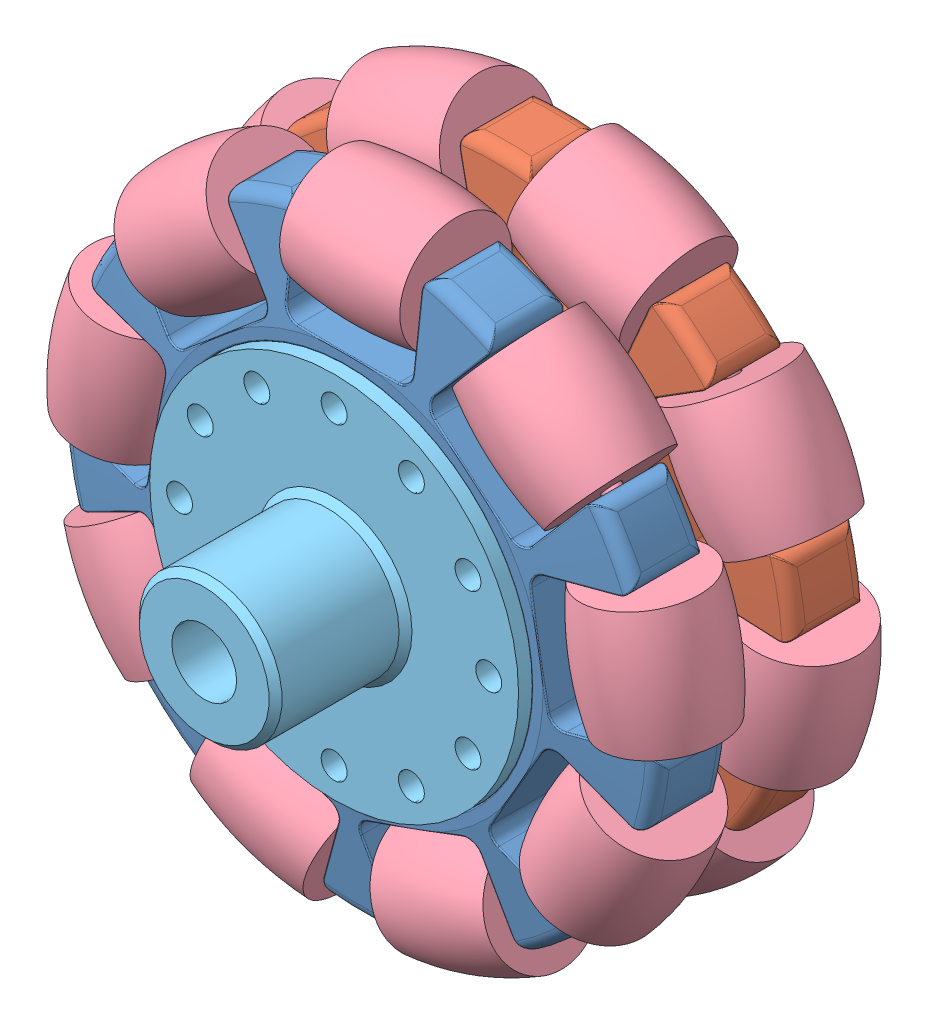
SolidWorks assembly banhxe, configuration Default. Lengths in mm.
Overall size (124.48 124.98 61.51).
22 component instances, 5 part files, 17 mates.
Components (placement in the parent):
- omniwheel_1-1: omniwheel_1 [Default] at (-17.0114 53.5739 73.2518) size (91.98 90.63 15.09)
- omniwheel_2-1: omniwheel_2 [Default] at (-17.0114 53.5739 37.2518) x (-0.5 -0.866025 0) z (0 0 -1) size (91.98 90.63 15.09)
- Part1^banhxe-1: Part1^banhxe [Default] at (-17.0114 53.5739 59.2518) x (-1 0 0) z (0 0 -1) size (56.8 56.8 18) (virtual)
- roller-1: roller [Default] at (-17.0114 132.519 53.0151) x (1 0 0) z (0 -0.314487 -0.949262) size (24.1 19 19)
- roller-3: roller [Default] at (33.7335 114.0494 53.0151) x (0.766044 -0.642788 0) z (-0.202148 -0.240911 -0.949262) size (24.1 19 19)
- roller-4: roller [Default] at (60.7343 67.2826 53.0151) x (0.173648 -0.984808 0) z (-0.309709 -0.05461 -0.949262) size (24.1 19 19)
- roller-5: roller [Default] at (51.357 14.1014 53.0151) x (-0.5 -0.866025 0) z (-0.272353 0.157243 -0.949262) size (24.1 19 19)
- roller-6: roller [Default] at (9.9894 -20.6102 53.0151) x (-0.939693 -0.34202 0) z (-0.107561 0.295521 -0.949262) size (24.1 19 19)
- roller-7: roller [Default] at (-44.0123 -20.6102 53.0151) x (-0.939693 0.34202 0) z (0.107561 0.295521 -0.949262) size (24.1 19 19)
- roller-8: roller [Default] at (-85.3799 14.1014 53.0151) x (-0.5 0.866025 0) z (0.272353 0.157243 -0.949262) size (24.1 19 19)
- roller-9: roller [Default] at (-94.7572 67.2826 53.0151) x (0.173648 0.984808 0) z (0.309709 -0.05461 -0.949262) size (24.1 19 19)
- roller-10: roller [Default] at (-67.7564 114.0494 53.0151) x (0.766044 0.642788 0) z (0.202148 -0.240911 -0.949262) size (24.1 19 19)
- roller-11: roller [Default] at (-17.5454 53.8822 51.7918) x (0.5 0.866025 0) z (-0.150538 0.086913 0.984776) size (24.1 19 19)
- roller-12: roller [Default] at (-17.6186 53.4669 51.7918) x (-0.173648 0.984808 0) z (-0.171186 -0.030185 0.984776) size (24.1 19 19)
- roller-13: roller [Default] at (-17.4078 53.1016 51.7918) x (-0.766044 0.642788 0) z (-0.111734 -0.133159 0.984776) size (24.1 19 19)
- roller-14: roller [Default] at (-17.0114 52.9574 51.7918) x (-1 0 0) z (0 -0.173827 0.984776) size (24.1 19 19)
- roller-15: roller [Default] at (-16.6151 53.1016 51.7918) x (-0.766044 -0.642788 0) z (0.111734 -0.133159 0.984776) size (24.1 19 19)
- roller-16: roller [Default] at (-16.4042 53.4669 51.7918) x (-0.173648 -0.984808 0) z (0.171186 -0.030185 0.984776) size (24.1 19 19)
- roller-17: roller [Default] at (-16.4775 53.8822 51.7918) x (0.5 -0.866025 0) z (0.150538 0.086913 0.984776) size (24.1 19 19)
- roller-18: roller [Default] at (-16.8006 54.1533 51.7918) x (0.939693 -0.34202 0) z (0.059452 0.163344 0.984776) size (24.1 19 19)
- roller-19: roller [Default] at (-17.2223 54.1533 51.7918) x (0.939693 0.34202 0) z (-0.059452 0.163344 0.984776) size (24.1 19 19)
- Part3^banhxe-1: Part3^banhxe [Default] at (-17.0114 53.5739 72.2518) size (56.8 56.8 23)
Mates (geometry in assembly coordinates):
- Concentric1: concentric: cylinder of omniwheel_1-1 through (-17.0114 53.5739 65.7518) axis (0 0 1) radius 14; cylinder of omniwheel_2-1 through (-17.0114 53.5739 44.7518) axis (0 0 -1) radius 14
- Concentric2: concentric: circle of omniwheel_1-1; circle of omniwheel_2-1
- InPlace1: in place: plane of omniwheel_1-1 through (-17.0114 47.6916 59.2518) normal (0 0 -1); plane of ? through (0 0 59.2518) normal (0 0 -1); moOrthogonalPlaneRef_w of omniwheel_1-1 through (-17.0114 47.6916 59.2518) normal (0 0 -1); unknown of ?; plane of omniwheel_1-1 through (-17.0114 47.6916 59.2518) normal (0 0 -1); plane of ? through (0 0 59.2518) normal (-1 0 0); plane of omniwheel_1-1 through (-17.0114 47.6916 59.2518) normal (0 0 -1); unknown of Part1^banhxe-1
- Coincident1: coincident: plane of omniwheel_1-1; plane of Part1^banhxe-1
- Coincident2: coincident: moOrthogonalPlaneRef_w of omniwheel_1-1 through (-17.0114 53.5739 59.2518) normal (0 1 0); plane of Part1^banhxe-1 through (-17.0114 53.5739 59.2518) normal (0 1 0)
- Coincident3: coincident: moOrthogonalPlaneRef_w of omniwheel_1-1 through (-17.0114 53.5739 59.2518) normal (1 0 0); plane of Part1^banhxe-1 through (-17.0114 53.5739 59.2518) normal (-1 0 0)
- Concentric3: concentric: cylinder of omniwheel_1-1 through (-7.2614 94.0739 65.7518) axis (-1 0 0) radius 1.5; cylinder of roller-1 through (-26.2614 94.0739 65.7518) axis (-1 0 0) radius 1.4
- Width1: width: plane of omniwheel_1-1 through (-26.7614 47.6916 65.7518) normal (1 0 0); plane of omniwheel_1-1 through (-7.2614 47.6916 65.7518) normal (-1 0 0); plane of roller-1 through (-26.2614 85.8752 68.468) normal (-1 0 0); plane of roller-1 through (-7.7614 85.8752 68.468) normal (1 0 0)
- Concentric4: concentric: cylinder of omniwheel_2-1 through (-47.2105 82.2677 44.7518) axis (-0.5 -0.866025 0) radius 1.5; cylinder of roller-11 through (-56.7105 65.8132 44.7518) axis (-0.5 -0.866025 0) radius 1.4
- Width2: width: plane of omniwheel_2-1 through (-16.7921 42.189 44.7518) normal (0.5 0.866025 0); plane of omniwheel_2-1 through (-7.0421 59.0765 44.7518) normal (-0.5 -0.866025 0); plane of roller-11 through (-64.0764 70.0659 43.2505) normal (-0.5 -0.866025 0); plane of roller-11 through (-54.8264 86.0874 43.2505) normal (0.5 0.866025 0)
- Coincident5: coincident: plane of omniwheel_2-1 through (-11.9171 50.6327 51.2518) normal (0 0 1); plane of Part1^banhxe-1 through (-17.0114 53.5739 51.2518) normal (0 0 -1)
- InPlace2: in place: plane of omniwheel_1-1 through (-17.0114 47.6916 72.2518) normal (0 0 1); plane of ? through (0 0 72.2518) normal (0 0 1); plane of omniwheel_1-1 through (-17.0114 47.6916 72.2518) normal (0 0 1); plane of ? through (0 0 72.2518) normal (0 1 0); plane of omniwheel_1-1 through (-17.0114 47.6916 72.2518) normal (0 0 1); plane of ? through (0 0 72.2518) normal (1 0 0); plane of omniwheel_1-1 through (-17.0114 47.6916 72.2518) normal (0 0 1); unknown of Part3^banhxe-1
- Coincident6: coincident: plane of omniwheel_1-1; plane of Part3^banhxe-1
- Coincident7: coincident: moOrthogonalPlaneRef_w of omniwheel_1-1 through (-17.0114 53.5739 72.2518) normal (0 1 0); plane of Part3^banhxe-1 through (-17.0114 53.5739 72.2518) normal (0 1 0)
- Coincident8: coincident: moOrthogonalPlaneRef_w of omniwheel_1-1 through (-17.0114 53.5739 72.2518) normal (-1 0 0); plane of Part3^banhxe-1 through (-17.0114 53.5739 72.2518) normal (1 0 0)
- Concentric6: concentric: cylinder of Part3^banhxe-1 through (-37.6228 65.4739 72.2518) axis (0 0 1) radius 2; cylinder of ? through (-37.6228 65.4739 112.0018) axis (0 0 1) radius 4.25
- Coincident7: coincident: plane of Part3^banhxe-1 through (-17.0114 53.5739 75.2518) normal (0 0 1); plane of ? through (-38.316 61.2808 75.2518) normal (0 0 -1)
